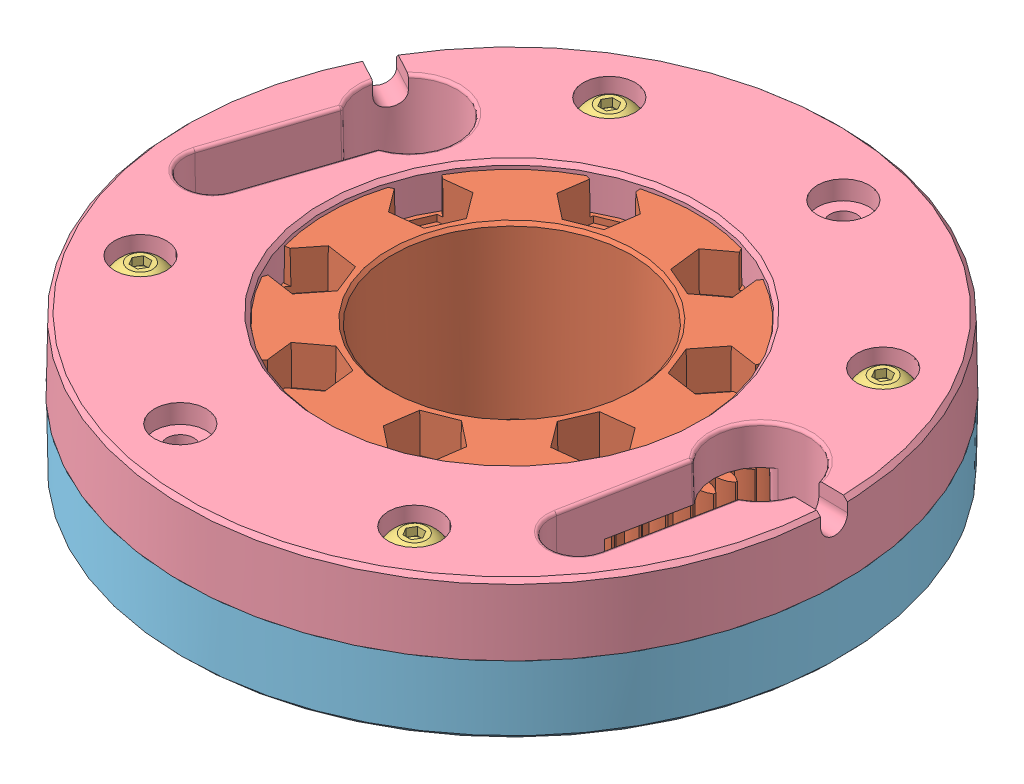
SolidWorks assembly 276-1810-LARGE, configuration Default. Lengths in mm.
Overall size (147.66 29.35 147.66).
11 component instances, 5 part files, 0 mates.
Components (placement in the parent):
- NUT-832-NYLOCK_ANY-1: NUT-832-NYLOCK_ANY [Default] at (-21.9884 -5.9803 -38.1663) x (-0.504401 0 -0.863469) z (-0.863469 0 0.504401) size (10.2 5.86 8.12)
- NUT-832-NYLOCK_ANY-2: NUT-832-NYLOCK_ANY [Default] at (-37.949 -6.0003 22.6355) x (-0.868559 0 -0.495586) z (-0.495586 0 0.868559) size (10.2 5.86 8.12)
- 276-1810-002-1: 276-1810-002 [Default] at (0.4322 -6.167 0.2149) x (0.918419 0 0.395609) z (-0.395609 0 0.918419) size (71.9 28.17 71.97)
- SCREW-832-0750_ANY-1: SCREW-832-0750_ANY [Default] at (22.8529 9.1048 38.5961) x (0 -1 0) z (0 0 1) size (21.26 7.92 7.92)
- SCREW-832-0750_ANY-2: SCREW-832-0750_ANY [Default] at (-37.949 9.1048 22.6355) x (0 -1 0) z (0 0 1) size (21.26 7.92 7.92)
- 276-1810-004-1: 276-1810-004 [Default] at (0.4322 -1.287 0.2149) x (0.504401 0 0.863469) z (-0.863469 0 0.504401) size (107.95 11.46 107.95)
- NUT-832-NYLOCK_ANY-3: NUT-832-NYLOCK_ANY [Default] at (38.8134 -5.9803 -22.2058) x (0.863469 0 -0.504401) z (-0.504401 0 -0.863469) size (10.2 5.86 8.12)
- SCREW-832-0750_ANY-3: SCREW-832-0750_ANY [Default] at (38.8134 9.1048 -22.2058) x (0 -1 0) z (0 0 1) size (21.26 7.92 7.92)
- SCREW-832-0750_ANY-4: SCREW-832-0750_ANY [Default] at (-21.9884 9.1048 -38.1663) x (0 -1 0) z (0 0 1) size (21.26 7.92 7.92)
- 276-1810-003-1: 276-1810-003 [Default] at (0.4322 -1.287 0.2149) x (-0.504401 0 -0.863469) z (-0.863469 0 0.504401) size (107.95 11.36 107.95)
- NUT-832-NYLOCK_ANY-4: NUT-832-NYLOCK_ANY [Default] at (22.8529 -5.9803 38.5961) x (-0.504401 0 -0.863469) z (-0.863469 0 0.504401) size (10.2 5.86 8.12)
